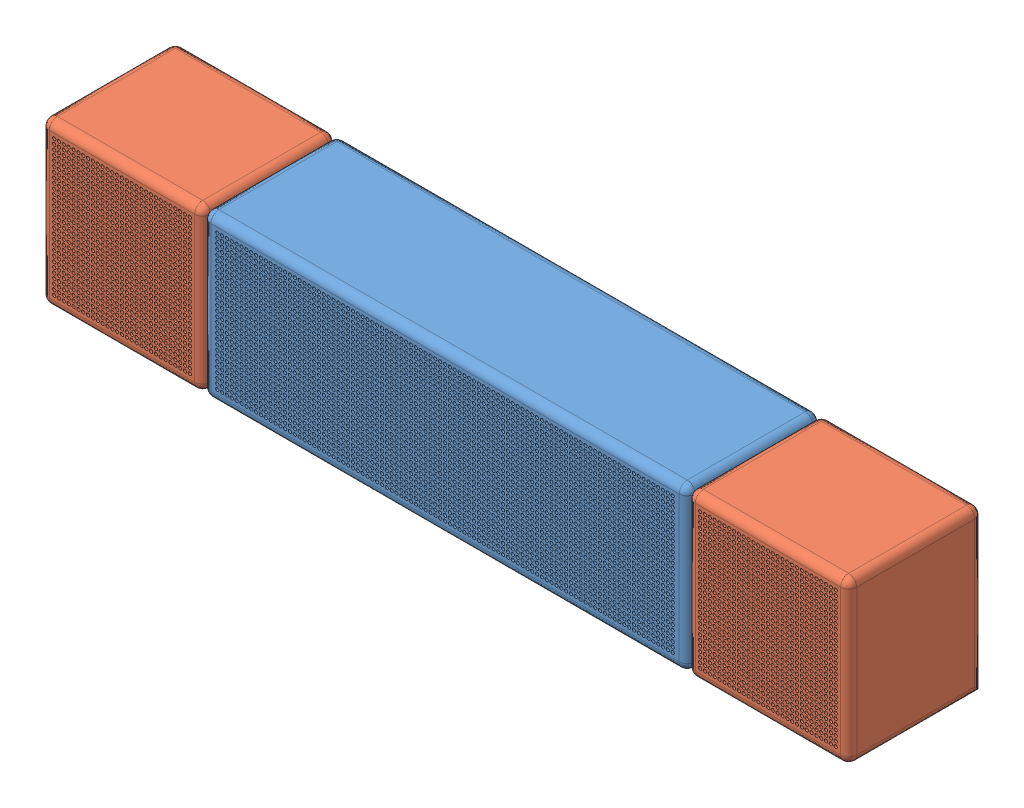
SolidWorks assembly Assem1, configuration Default. Lengths in mm.
Overall size (500 100 83).
3 component instances, 2 part files, 2 mates.
Components (placement in the parent):
- project alpha-1: project alpha [Default] at (108.333 109.2262 264.3566) size (300 100 83)
- prjalp2-1: prjalp2 [Default] at (-91.667 109.2262 264.3566) size (100 100 83)
- prjalp2-2: prjalp2 [Default] at (308.333 109.2262 264.3566) size (100 100 83)
Mates (geometry in assembly coordinates):
- Coincident2: coincident: point of project alpha-1; point of prjalp2-1
- Coincident3: coincident: point of project alpha-1; point of prjalp2-2
